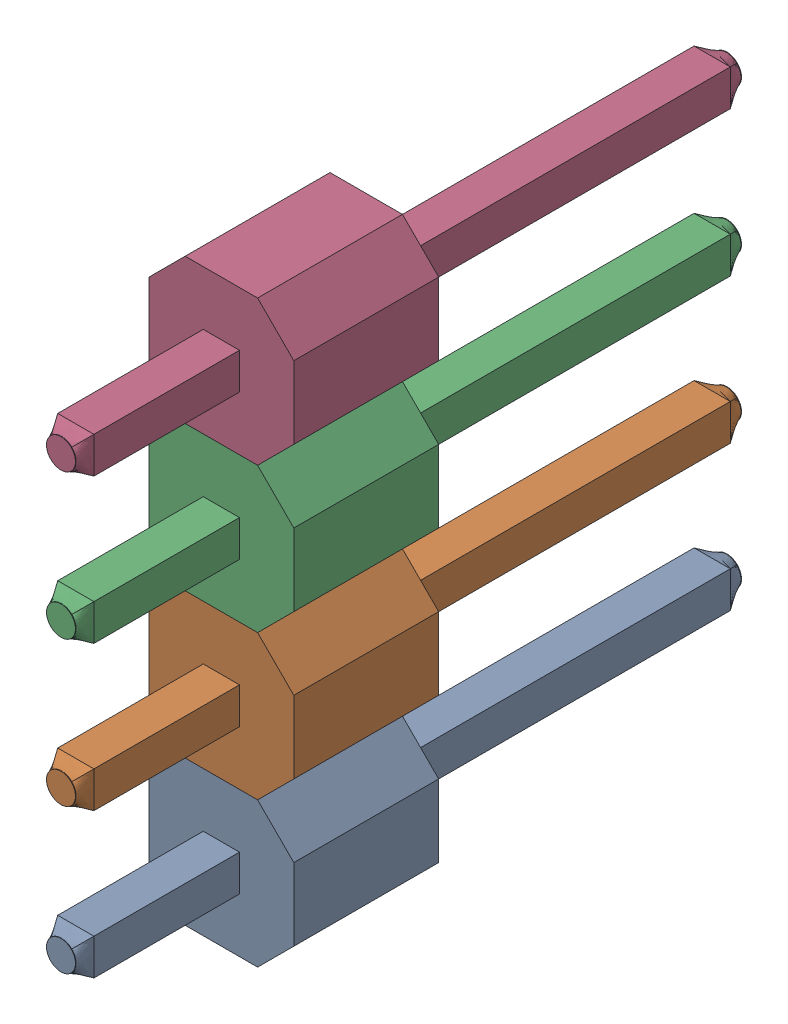
SolidWorks assembly Male Header 4 Pin, configuration Default. Lengths in mm.
Overall size (2.54 10.16 11.76).
4 component instances, 1 part files, 0 mates.
Components (placement in the parent):
- Male Header Pin-1: Male Header Pin [Default] at (-59.6963 14.7644 21.6487) size (2.54 2.54 11.76)
- Male Header Pin-2: Male Header Pin [Default] at (-59.6963 17.3044 21.6487) size (2.54 2.54 11.76)
- Male Header Pin-3: Male Header Pin [Default] at (-59.6963 19.8444 21.6487) size (2.54 2.54 11.76)
- Male Header Pin-4: Male Header Pin [Default] at (-59.6963 22.3844 21.6487) size (2.54 2.54 11.76)
